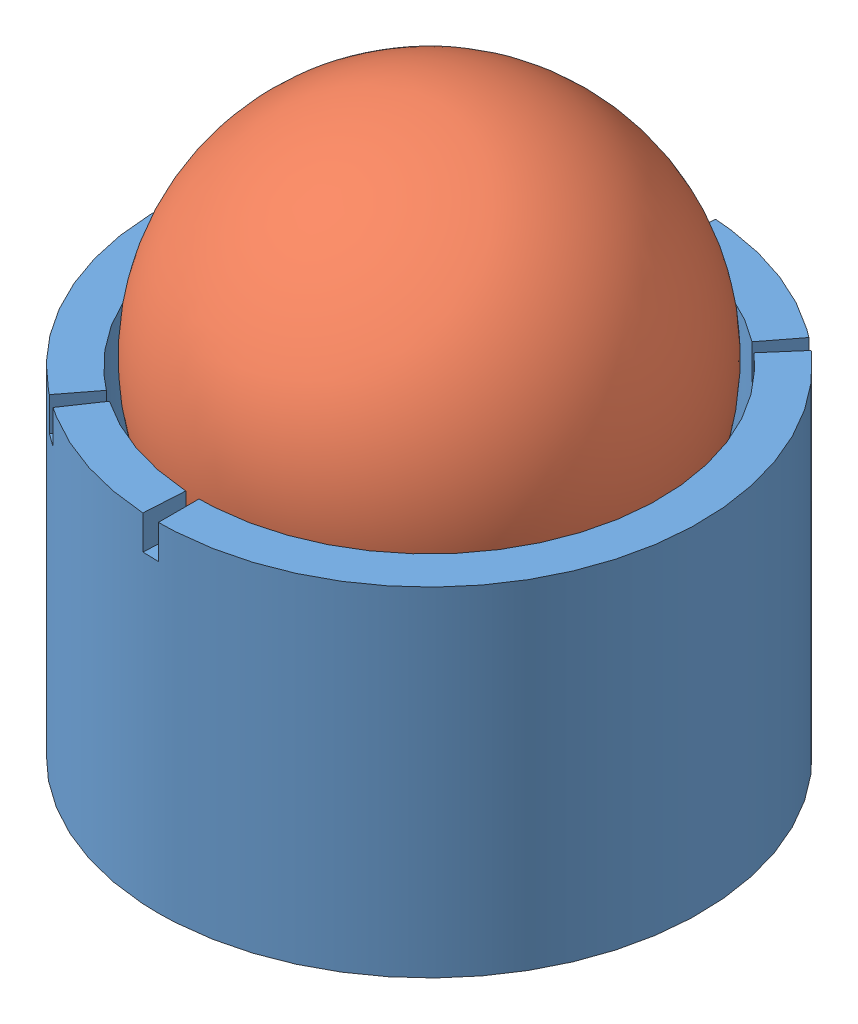
SolidWorks assembly Bougie_complete_Blanche, configuration Défaut. Lengths in mm.
Overall size (80 89.69 80).
2 component instances, 2 part files, 1 mates.
Components (placement in the parent):
- Bougie_Blanche-1: Bougie_Blanche [Défaut] at (-26.1532 -23.3286 0) size (80 50 80)
- Balle_Tennis_2-1: Balle_Tennis_2 [Défaut] at (-26.1532 27.8198 0) x (0.985823 0.158602 0.054752) z (-0.048841 -0.040931 0.997968) size (65 65 65)
Mates (geometry in assembly coordinates):
- Coaxiale1: concentric: cylinder of Bougie_Blanche-1 through (-26.1532 26.6714 0) axis (0 -1 0) radius 34; sphere of Balle_Tennis_2-1
